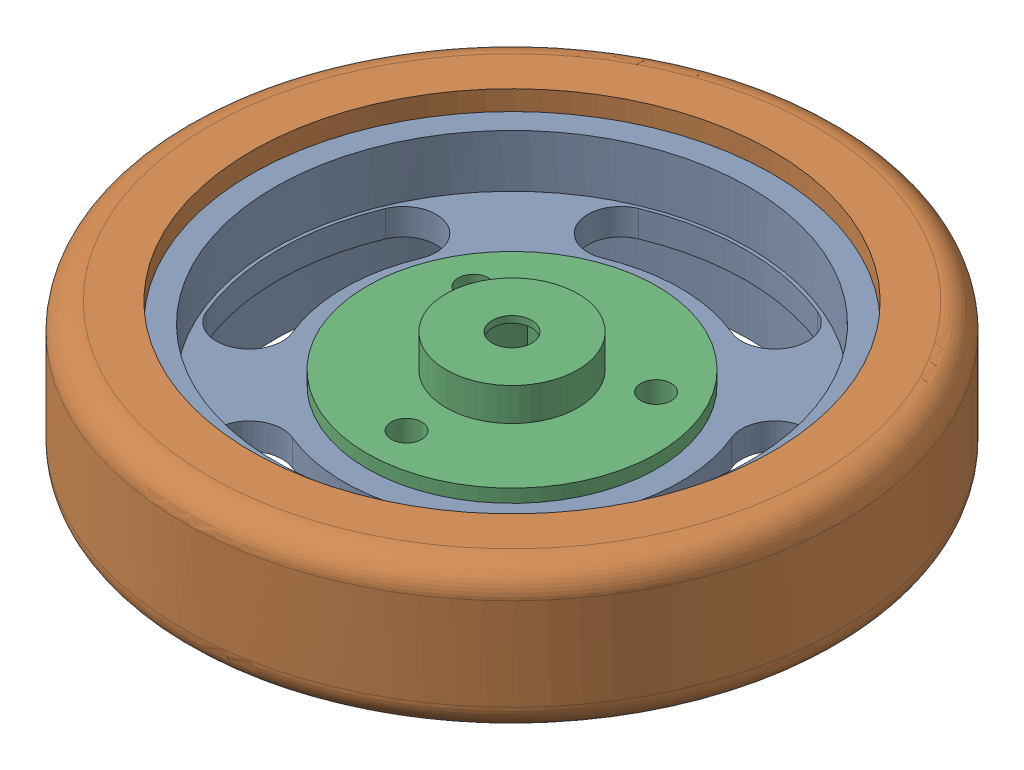
SolidWorks assembly Wheel, configuration Varsayılan. Lengths in mm.
Overall size (61.01 12.5 61.01).
3 component instances, 3 part files, 5 mates.
Components (placement in the parent):
- WheelBase-1: WheelBase [Varsayılan] at origin size (43.5 11 43.5)
- Tire-1: Tire [Varsayılan] at (0 1 0) x (-0.252554 0 -0.967583) z (-0.967583 0 0.252554) size (50 11 50)
- WheelLock-1: WheelLock [Varsayılan] at origin size (22 4.5 22)
Mates (geometry in assembly coordinates):
- Concentric7: concentric: cylinder of WheelBase-1 through (0 0 0) axis (0 1 0) radius 11; cylinder of WheelLock-1 through (0 2 0) axis (0 -1 0) radius 11
- Concentric8: concentric: cylinder of WheelBase-1 through (6.9282 -5 -4) axis (0 1 0) radius 1.15; cylinder of WheelLock-1 through (6.9282 2 -4) axis (0 -1 0) radius 1.15
- Coincident3: coincident: plane of WheelBase-1 through (0 0 0) normal (0 1 0); plane of WheelLock-1 through (0 0 0) normal (0 -1 0)
- Concentric9: concentric anti-aligned: cylinder of WheelBase-1 through (0 0 0) axis (0 -1 0) radius 19.75; cylinder of Tire-1 through (0 1 0) axis (0 1 0) radius 25
- Coincident4: coincident aligned: plane of WheelBase-1 through (19.75 1 0) normal (0 1 0); plane of Tire-1 through (-5.4931 1 -21.0449) normal (0 1 0)
